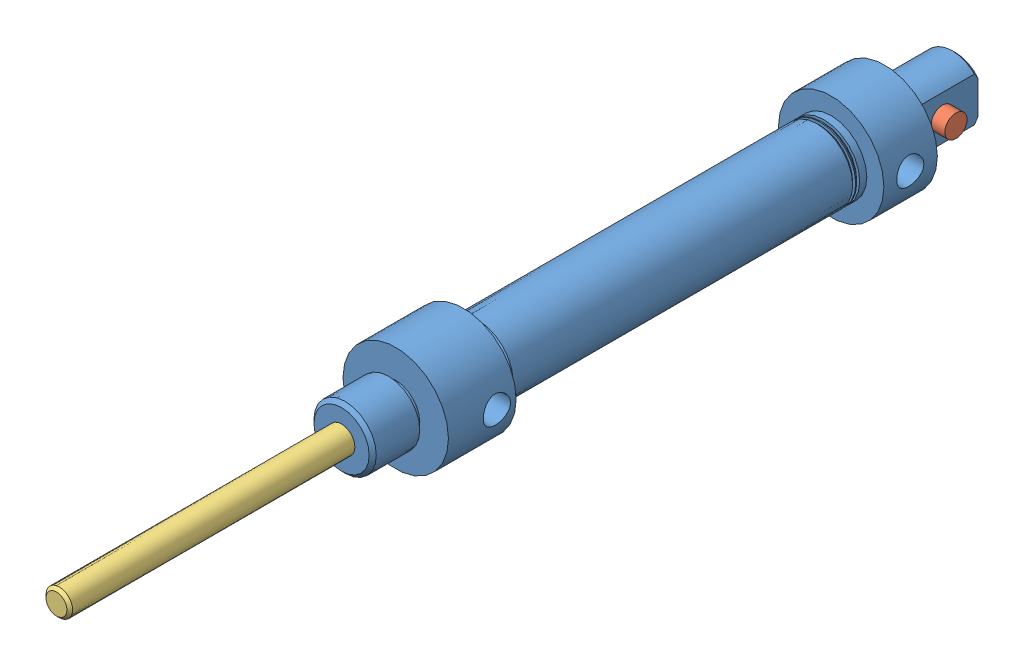
SolidWorks assembly A07015DP, configuration Default. Lengths in mm.
Overall size (18.8 18.8 160.27).
3 component instances, 3 part files, 4 mates.
Components (placement in the parent):
- A07015DP-MainBody-1: A07015DP-MainBody [Default] at (-13.8999 28.3451 -10.4685) x (0 0 -1) z (1 0 0) size (109.47 18.8 18.8)
- A07015DP-Pin-1: A07015DP-Pin [Default] at (-13.8999 28.3451 -113.5925) size (12.7 3.96 3.96)
- A07015DP-Rod-1: A07015DP-Rod [Default] at (-13.8999 28.3451 608.8156) x (0 0 -1) z (-0.737199 -0.675676 0) size (91.31 11.11 11.11)
Mates (geometry in assembly coordinates):
- LimitDistance1: limit distance = 38.1 mm anti-aligned: plane of A07015DP-MainBody-1 through (-13.8999 28.3451 -89.0815) normal (0 0 1); plane of A07015DP-Rod-1 through (-13.8999 28.3451 -50.9815) normal (0 0 -1)
- Concentric1: concentric aligned: cylinder of A07015DP-MainBody-1 through (-13.8999 28.3451 -10.4685) axis (0 0 -1) radius 2.3749; cylinder of A07015DP-Rod-1 through (-13.8999 28.3451 47.0488) axis (0 0 -1) radius 2.3749
- Concentric3: concentric anti-aligned: cylinder of A07015DP-MainBody-1 through (-23.4406 28.3451 -113.5925) axis (1 0 0) radius 1.9812; cylinder of A07015DP-Pin-1 through (-7.5499 28.3451 -113.5925) axis (-1 0 0) radius 1.9812
- Width1: width anti-aligned: plane of A07015DP-Pin-1 through (-20.2499 28.3451 -113.5925) normal (-1 0 0); plane of A07015DP-Pin-1 through (-7.5499 28.3451 -113.5925) normal (1 0 0); plane of A07015DP-MainBody-1 through (-9.9629 32.2659 -99.2356) normal (1 0 0); plane of A07015DP-MainBody-1 through (-17.8369 32.2659 -99.2356) normal (-1 0 0)
